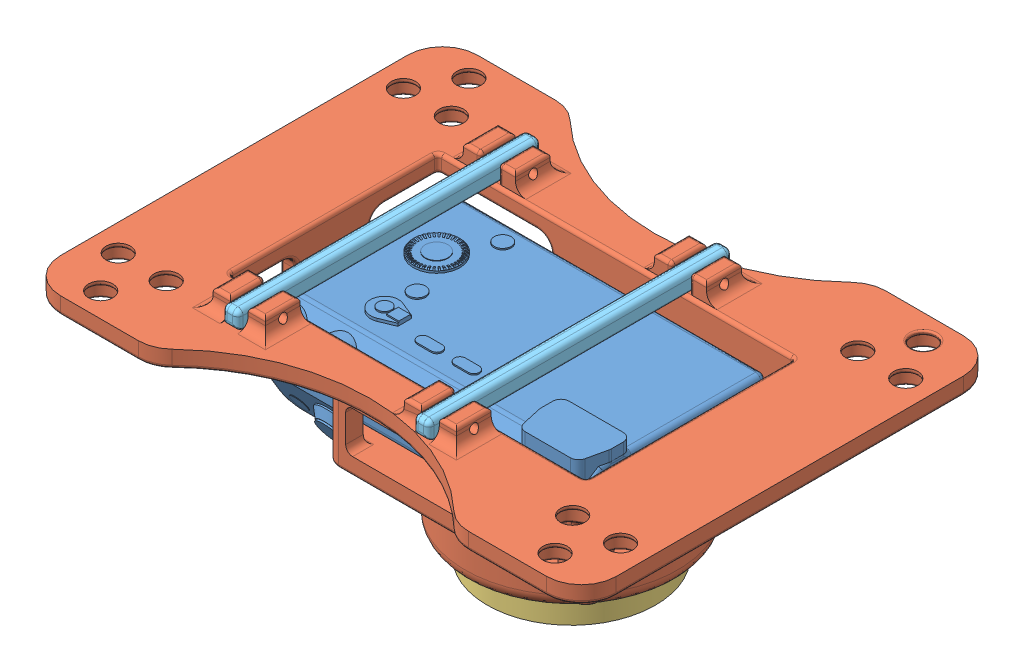
SolidWorks assembly Sony_NEX7_Mount2, configuration Default. Lengths in mm.
Overall size (203.2 102.11 152.4).
18 component instances, 6 part files, 43 mates.
Components (placement in the parent):
- Sony NEX7 Download-1: Sony NEX7 Download [Default] at (17 -11.8522 -33.5) x (-1 0 0) z (0 1 0) size (119.12 68.2 44.02)
- Sony_NEX7_Mount_2-1: Sony_NEX7_Mount_2 [Default] at origin size (203.2 63.97 152.4)
- NEX_7_Lens-1: NEX_7_Lens [Default] at (19.85 -32.3522 -1.85) x (-0.588992 0 0.808139) z (0 -1 0) size (61.52 61.52 28.57)
- IR_Sensor-1: IR_Sensor [Default] at (-35.2645 -44.45 11.4896) x (-1 0 0) z (0 1 0) size (11.67 22.86 5.71)
- Zenumuse Dampening Ball-1: Zenumuse Dampening Ball [Default] at (-83.058 33.1863 67.31) size (14.75 16 14.75) (hidden)
- Zenumuse Dampening Ball-2: Zenumuse Dampening Ball [Default] at (-91.821 33.1863 52.132) x (0.915715 0 -0.401829) z (0.401829 0 0.915715) size (14.75 16 14.75) (hidden)
- Zenumuse Dampening Ball-3: Zenumuse Dampening Ball [Default] at (-74.295 33.1863 52.132) size (14.75 16 14.75) (hidden)
- Zenumuse Dampening Ball-5: Zenumuse Dampening Ball [Default] at (74.295 33.1863 -52.132) size (14.75 16 14.75) (hidden)
- Zenumuse Dampening Ball-6: Zenumuse Dampening Ball [Default] at (74.295 33.1863 52.132) size (14.75 16 14.75) (hidden)
- Zenumuse Dampening Ball-7: Zenumuse Dampening Ball [Default] at (83.058 33.1863 -67.31) size (14.75 16 14.75) (hidden)
- Zenumuse Dampening Ball-8: Zenumuse Dampening Ball [Default] at (83.058 33.1863 67.31) size (14.75 16 14.75) (hidden)
- Zenumuse Dampening Ball-9: Zenumuse Dampening Ball [Default] at (-91.821 33.1863 -52.132) size (14.75 16 14.75) (hidden)
- Zenumuse Dampening Ball-10: Zenumuse Dampening Ball [Default] at (91.821 33.1863 52.132) size (14.75 16 14.75) (hidden)
- Zenumuse Dampening Ball-11: Zenumuse Dampening Ball [Default] at (-74.295 33.1863 -52.132) size (14.75 16 14.75) (hidden)
- Zenumuse Dampening Ball-12: Zenumuse Dampening Ball [Default] at (91.821 33.1863 -52.132) size (14.75 16 14.75) (hidden)
- Zenumuse Dampening Ball-13: Zenumuse Dampening Ball [Default] at (-83.058 33.1863 -67.31) size (14.75 16 14.75) (hidden)
- Retaining Bar-1: Retaining Bar [Default] at (0 6.35 0) x (1 0 0) z (0 1 0) size (5.77 111 6.35)
- Retaining Bar-2: Retaining Bar [Default] at (69.8204 6.35 0) x (1 0 0) z (0 1 0) size (5.77 111 6.35)
Mates (geometry in assembly coordinates):
- Coincident10: coincident aligned: plane of Sony NEX7 Download-1 through (17 6.35 33.5) normal (0 1 0); plane of Sony_NEX7_Mount_2-1 through (0 6.35 0) normal (0 1 0)
- Parallel3: parallel aligned: plane of Sony NEX7 Download-1; plane of assembly through (0 0 0) normal (0 0 1)
- Coincident5: coincident aligned: plane of Sony_NEX7_Mount_2-1 through (0 0 0) normal (0 1 0); plane of assembly through (0 0 0) normal (0 1 0)
- Coincident3: coincident aligned: plane of Sony_NEX7_Mount_2-1 through (0 0 0) normal (0 0 1); plane of assembly through (0 0 0) normal (0 0 1)
- Coincident4: coincident aligned: plane of Sony_NEX7_Mount_2-1 through (0 0 0) normal (1 0 0); plane of assembly through (0 0 0) normal (1 0 0)
- Coincident6: coincident anti-aligned: plane of Sony NEX7 Download-1; plane of Sony_NEX7_Mount_2-1 through (0 0 0) normal (1 0 0)
- Coincident7: coincident aligned: plane of Sony NEX7 Download-1; plane of Sony_NEX7_Mount_2-1 through (0 0 0) normal (0 0 1)
- Concentric1: concentric anti-aligned: circle of Sony NEX7 Download-1; cylinder of NEX_7_Lens-1 through (19.85 -60.9272 -1.85) axis (0 1 0) radius 30.7594
- Coincident9: coincident anti-aligned: plane of Sony NEX7 Download-1 through (19.85 -32.3522 -1.85) normal (0 -1 0); plane of NEX_7_Lens-1 through (19.85 -32.3522 -1.85) normal (0 1 0)
- Coincident12: coincident anti-aligned: plane of IR_Sensor-1 through (-35.2645 -44.45 11.4896) normal (0 -1 0); plane of Sony_NEX7_Mount_2-1 through (0 -44.45 13.335) normal (0 1 0)
- Parallel6: parallel anti-aligned: plane of IR_Sensor-1 through (-29.4288 -38.735 3.2346) normal (1 0 0); plane of Sony_NEX7_Mount_2-1 through (-23.9014 -22.86 0) normal (-1 0 0)
- Coincident14: coincident: line of Sony NEX7 Download-1 through (-38.0878 -38.5522 19.7446) axis (1 0 0); plane of IR_Sensor-1 through (-29.4288 -38.735 19.7446) normal (0 0 1)
- Slot1: slot aligned: plane of Sony_NEX7_Mount_2-1 through (23.0694 -14.4176 76.201) normal (-1 0 0); cylinder of Sony NEX7 Download-1 through (19.85 -14.4176 -26.2) axis (0 0 -1) radius 3.25; cylinder of Sony_NEX7_Mount_2-1 through (19.85 -16.8687 76.201) axis (0 0 -1) radius 3.2195
- Parallel7: parallel aligned: plane of Sony NEX7 Download-1 through (17 1.4478 33.5) normal (0 1 0); plane of assembly through (0 0 0) normal (0 1 0)
- Concentric2: concentric aligned: cylinder of Sony_NEX7_Mount_2-1 through (-83.058 6.35 67.31) axis (0 -1 0) radius 4.445; cylinder of Zenumuse Dampening Ball-1 through (-83.058 25.1863 67.31) axis (0 -1 0) radius 2.64
- Concentric3: concentric aligned: cylinder of Sony_NEX7_Mount_2-1 through (-91.821 6.35 52.132) axis (0 -1 0) radius 4.445; cylinder of Zenumuse Dampening Ball-2 through (-91.821 25.1863 52.132) axis (0 -1 0) radius 2.64
- Concentric4: concentric aligned: cylinder of Sony_NEX7_Mount_2-1 through (-74.295 6.35 52.132) axis (0 -1 0) radius 4.445; circle of Zenumuse Dampening Ball-3
- Concentric5: concentric aligned: cylinder of Sony_NEX7_Mount_2-1 through (-83.058 6.35 -67.31) axis (0 -1 0) radius 4.445; cylinder of Zenumuse Dampening Ball-13 through (-83.058 25.1863 -67.31) axis (0 -1 0) radius 2.64
- Concentric6: concentric aligned: cylinder of Sony_NEX7_Mount_2-1 through (-91.821 6.35 -52.132) axis (0 -1 0) radius 4.445; cylinder of Zenumuse Dampening Ball-9 through (-91.821 25.1863 -52.132) axis (0 -1 0) radius 2.64
- Concentric7: concentric aligned: cylinder of Sony_NEX7_Mount_2-1 through (-74.295 6.35 -52.132) axis (0 -1 0) radius 4.445; cylinder of Zenumuse Dampening Ball-11 through (-74.295 25.1863 -52.132) axis (0 -1 0) radius 2.64
- Concentric8: concentric aligned: cylinder of Sony_NEX7_Mount_2-1 through (83.058 6.35 -67.31) axis (0 -1 0) radius 4.445; circle of Zenumuse Dampening Ball-7
- Concentric9: concentric aligned: cylinder of Sony_NEX7_Mount_2-1 through (91.821 6.35 -52.132) axis (0 -1 0) radius 4.445; circle of Zenumuse Dampening Ball-12
- Concentric10: concentric aligned: cylinder of Sony_NEX7_Mount_2-1 through (74.295 6.35 -52.132) axis (0 -1 0) radius 4.445; circle of Zenumuse Dampening Ball-5
- Concentric11: concentric aligned: cylinder of Sony_NEX7_Mount_2-1 through (91.821 6.35 52.132) axis (0 -1 0) radius 4.445; cylinder of Zenumuse Dampening Ball-10 through (91.821 25.1863 52.132) axis (0 -1 0) radius 2.64
- Concentric12: concentric aligned: cylinder of Sony_NEX7_Mount_2-1 through (83.058 6.35 67.31) axis (0 -1 0) radius 4.445; circle of Zenumuse Dampening Ball-8
- Concentric13: concentric aligned: cylinder of Sony_NEX7_Mount_2-1 through (74.295 6.35 52.132) axis (0 -1 0) radius 4.445; circle of Zenumuse Dampening Ball-6
- Coincident27: coincident aligned: plane of Zenumuse Dampening Ball-2 through (-89.4035 41.1863 51.0712) normal (0 1 0); plane of Zenumuse Dampening Ball-9 through (-89.181 41.1863 -52.132) normal (0 1 0)
- Coincident28: coincident aligned: plane of Zenumuse Dampening Ball-2 through (-89.4035 41.1863 51.0712) normal (0 1 0); plane of Zenumuse Dampening Ball-13 through (-80.418 41.1863 -67.31) normal (0 1 0)
- Coincident32: coincident aligned: plane of Zenumuse Dampening Ball-2 through (-89.4035 41.1863 51.0712) normal (0 1 0); plane of Zenumuse Dampening Ball-6 through (76.935 41.1863 52.132) normal (0 1 0)
- Coincident33: coincident aligned: plane of Zenumuse Dampening Ball-2 through (-89.4035 41.1863 51.0712) normal (0 1 0); plane of Zenumuse Dampening Ball-10 through (94.461 41.1863 52.132) normal (0 1 0)
- Coincident36: coincident aligned: plane of Zenumuse Dampening Ball-2 through (-89.4035 41.1863 51.0712) normal (0 1 0); plane of Zenumuse Dampening Ball-8 through (85.698 41.1863 67.31) normal (0 1 0)
- Coincident38: coincident aligned: plane of Zenumuse Dampening Ball-2 through (-89.4035 41.1863 51.0712) normal (0 1 0); plane of Zenumuse Dampening Ball-5 through (76.935 41.1863 -52.132) normal (0 1 0)
- Coincident39: coincident aligned: plane of Zenumuse Dampening Ball-2 through (-89.4035 41.1863 51.0712) normal (0 1 0); plane of Zenumuse Dampening Ball-7 through (85.698 41.1863 -67.31) normal (0 1 0)
- Coincident40: coincident aligned: plane of Zenumuse Dampening Ball-2 through (-89.4035 41.1863 51.0712) normal (0 1 0); plane of Zenumuse Dampening Ball-12 through (94.461 41.1863 -52.132) normal (0 1 0)
- Coincident41: coincident aligned: plane of Zenumuse Dampening Ball-2 through (-89.4035 41.1863 51.0712) normal (0 1 0); plane of Zenumuse Dampening Ball-1 through (-80.418 41.1863 67.31) normal (0 1 0)
- Coincident42: coincident aligned: plane of Zenumuse Dampening Ball-2 through (-89.4035 41.1863 51.0712) normal (0 1 0); plane of Zenumuse Dampening Ball-3 through (-71.655 41.1863 52.132) normal (0 1 0)
- Coincident43: coincident aligned: plane of Zenumuse Dampening Ball-2 through (-89.4035 41.1863 51.0712) normal (0 1 0); plane of Zenumuse Dampening Ball-11 through (-71.655 41.1863 -52.132) normal (0 1 0)
- InPlace1: in place: plane of Sony_NEX7_Mount_2-1 through (0 6.35 0) normal (0 1 0); plane of Retaining Bar-1 through (0 6.35 0) normal (0 1 0); moOrthogonalPlaneRef_w of Sony_NEX7_Mount_2-1 through (0 6.35 0) normal (0 1 0); plane of Retaining Bar-1 through (0 6.35 0) normal (0 0 -1); plane of Sony_NEX7_Mount_2-1 through (0 6.35 0) normal (0 1 0); line of Retaining Bar-1 through (-55 0 6.35) axis (0 1 0); plane of Sony_NEX7_Mount_2-1 through (0 6.35 0) normal (0 1 0); unknown of Retaining Bar-1
- Coincident44: coincident aligned: plane of Sony_NEX7_Mount_2-1; plane of Retaining Bar-1
- Coincident45: coincident aligned: moOrthogonalPlaneRef_w of Sony_NEX7_Mount_2-1 through (0 6.35 0) normal (0 0 -1); plane of Retaining Bar-1 through (0 6.35 0) normal (0 0 -1)
- Coincident46: coincident anti-aligned: moOrthogonalPlaneRef_w of Sony_NEX7_Mount_2-1 through (0 6.35 0) normal (-1 0 0); plane of Retaining Bar-1
- Concentric14: concentric anti-aligned: cylinder of Sony_NEX7_Mount_2-1 through (12.7 9.525 -45.72) axis (-1 0 0) radius 1.5875; cylinder of Retaining Bar-2 through (25.0783 9.525 -45.72) axis (1 0 0) radius 1.7844
- Concentric15: concentric anti-aligned: cylinder of Sony_NEX7_Mount_2-1 through (12.7 9.525 45.72) axis (-1 0 0) radius 1.5875; cylinder of Retaining Bar-2 through (25.0783 9.525 45.72) axis (1 0 0) radius 1.7844
